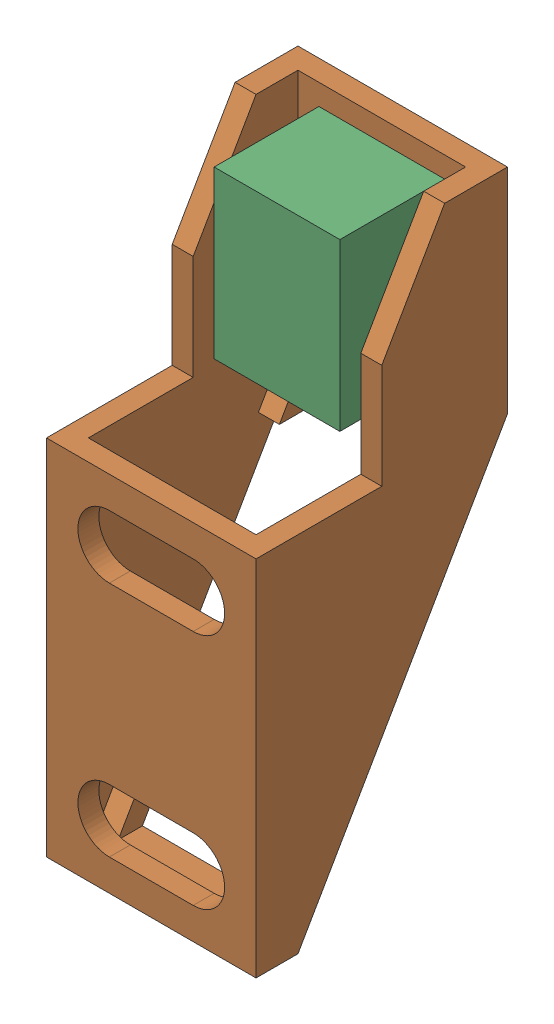
SolidWorks assembly Element, configuration Default. Lengths in mm.
Overall size (10 27.52 13.64).
3 component instances, 3 part files, 0 mates.
Components (placement in the parent):
- Needle-1: Needle [Default] at origin size (1.46 6.25 3.18)
- House-1: House [Default] at (-194.418 123.0355 -85.6815) x (1 0 0) z (0 -1 0) size (10 12 27.52)
- Connector-1: Connector [Default] at (-194.418 120.8597 -86.2072) x (1 0 0) z (0 -1 0) size (6 5 7.93)
